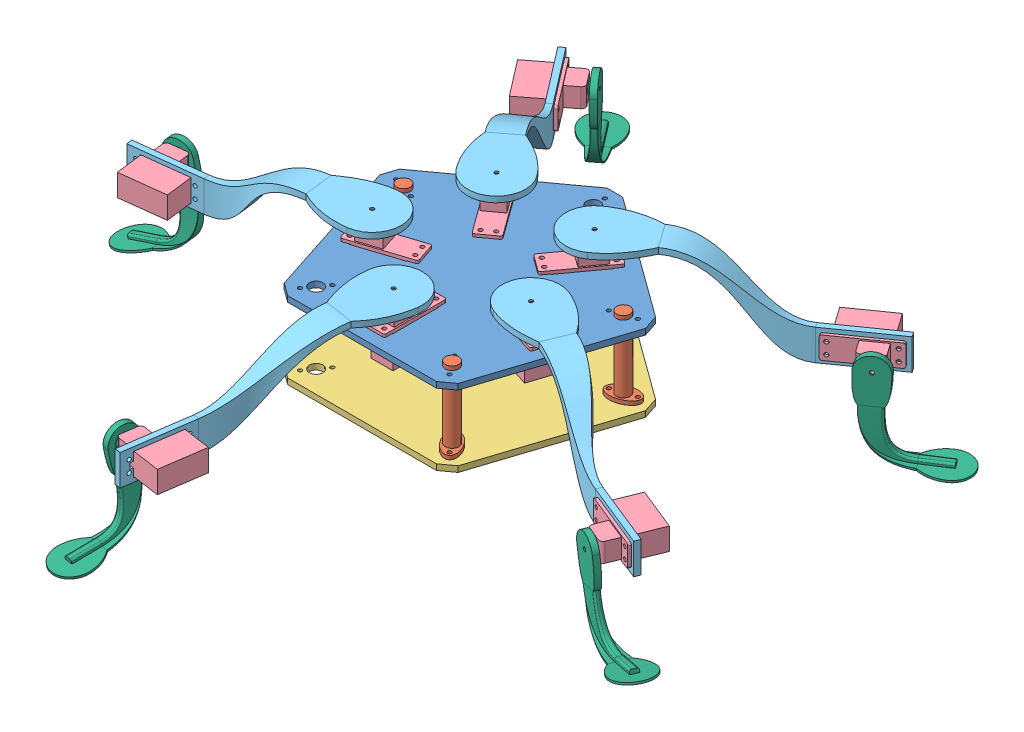
SolidWorks assembly robot1_assemblage, configuration Défaut. Lengths in mm.
Overall size (374.65 85.77 360.41).
25 component instances, 6 part files, 64 mates.
Components (placement in the parent):
- robot1_centre-1: robot1_centre [Défaut] at (-8.837 -2.6667 7.082) size (137.98 3 131.23)
- robot1_pilier-1: robot1_pilier [Défaut] at (48.2264 -19.6667 -11.459) x (0.951057 0 -0.309017) z (0.309017 0 0.951057) size (16 44 9)
- robot1_pilier-2: robot1_pilier [Défaut] at (26.4301 -19.6667 55.6231) x (-0.587785 0 -0.809017) z (0.809017 0 -0.587785) size (16 44 9)
- robot1_pilier-3: robot1_pilier [Défaut] at (-65.9004 -19.6667 -11.459) x (0.951057 0 0.309017) z (-0.309017 0 0.951057) size (16 44 9)
- robot1_fond-1: robot1_fond [Défaut] at (-8.837 -39.6667 7.082) size (137.98 3 131.23)
- servo2-3: servo2 [Défaut] at (17.7099 0.3333 9.8405) x (-0.309017 0 0.951057) z (0 1 0) size (11.43 32.26 30.46)
- servo2-4: servo2 [Défaut] at (-3.257 0.3333 33.182) x (-1 0 0) z (0 1 0) size (11.43 32.26 30.46)
- robot1_bras-1: robot1_bras [Défaut] at (32.4913 11.5713 20.6524) x (0.375024 0 -0.927015) z (0.927015 0 0.375024) size (30 43 135)
- servo2-5: servo2 [Défaut] at (112.2188 -14.5787 63.6934) x (0 -1 0) z (-0.375024 0 0.927015) size (11.43 32.26 30.46)
- robot1_bras-2: robot1_bras [Défaut] at (-8.972 11.5713 50.581) x (0.989601 0 0.143839) z (-0.143839 0 0.989601) size (30 43 135)
- servo2-6: servo2 [Défaut] at (1.7715 0.3333 -17.4718) x (0.809017 0 0.587785) z (0 1 0) size (11.43 32.26 30.46)
- servo2-7: servo2 [Défaut] at (-28.6925 0.3333 -10.7535) x (0.809017 0 -0.587785) z (0 1 0) size (11.43 32.26 30.46)
- servo2-8: servo2 [Défaut] at (-31.9352 0.3333 20.4543) x (-0.309017 0 -0.951057) z (0 1 0) size (11.43 32.26 30.46)
- robot1_bras-3: robot1_bras [Défaut] at (16.6219 11.5713 -28.1887) x (-0.576983 0 -0.816756) z (0.816756 0 -0.576983) size (30 43 135)
- robot1_bras-4: robot1_bras [Défaut] at (-34.2958 11.5713 -28.1887) x (-0.792689 0 0.609626) z (-0.609626 0 -0.792689) size (30 43 135)
- robot1_bras-5: robot1_bras [Défaut] at (-50.2487 11.5713 20.3956) x (0.119564 0 0.992826) z (-0.992826 0 0.119564) size (30 43 135)
- servo2-9: servo2 [Défaut] at (95.9406 -14.5787 -71.9785) x (0 -1 0) z (0.576983 0 0.816756) size (11.43 32.26 30.46)
- servo2-10: servo2 [Défaut] at (-81.2657 -14.8487 -105.6667) x (0 -1 0) z (0.792689 0 -0.609626) size (11.43 32.26 30.46)
- servo2-11: servo2 [Défaut] at (-140.8484 -14.5787 21.2341) x (0 -1 0) z (-0.119564 0 -0.992826) size (11.43 32.26 30.46)
- servo2-12: servo2 [Défaut] at (-31.8207 -14.8487 138.2562) x (0 -1 0) z (-0.989601 0 -0.143839) size (11.43 32.26 30.46)
- robot1_pied-2: robot1_pied [Défaut] at (116.6354 -20.2937 -72.8388) x (0.576983 0 0.816756) z (-0.816415 0.028897 0.576743) size (21.04 49.89 47.7)
- robot1_pied-3: robot1_pied [Défaut] at (-82.9644 -20.5637 -126.3097) x (0.792689 0 -0.609626) z (0.609626 0 0.792689) size (21.04 49.89 47.7)
- robot1_pied-4: robot1_pied [Défaut] at (-159.4662 -20.2937 12.157) x (-0.119564 0 -0.992826) z (0.962903 0.243662 -0.115961) size (21.04 49.89 47.7)
- robot1_pied-5: robot1_pied [Défaut] at (-45.4445 -20.5637 153.8578) x (-0.989601 0 -0.143839) z (0.142047 0.157336 -0.977276) size (21.04 49.89 47.7)
- robot1_pied-6: robot1_pied [Défaut] at (124.1334 -20.2937 80.6362) x (-0.375024 0 0.927015) z (-0.901976 -0.230852 -0.364894) size (21.04 49.89 47.7)
Mates (geometry in assembly coordinates):
- Coaxiale4: concentric aligned: circle of robot1_centre-1; circle of robot1_pilier-1
- Coaxiale5: concentric aligned: circle of robot1_centre-1; circle of robot1_pilier-2
- Coaxiale6: concentric aligned: circle of robot1_centre-1; circle of robot1_pilier-3
- Coaxiale7: concentric aligned: circle of robot1_centre-1; circle of robot1_pilier-1
- Coaxiale8: concentric aligned: circle of robot1_centre-1; circle of robot1_pilier-2
- Coaxiale9: concentric aligned: circle of robot1_centre-1; circle of robot1_pilier-3
- Coïncidente15: coincident anti-aligned: plane of robot1_centre-1 through (-8.837 -2.6667 7.082) normal (0 -1 0); plane of robot1_pilier-3 through (-65.9004 -2.6667 -11.459) normal (0 1 0)
- Coïncidente16: coincident anti-aligned: plane of robot1_centre-1 through (-8.837 -2.6667 7.082) normal (0 -1 0); plane of robot1_pilier-1 through (48.2264 -2.6667 -11.459) normal (0 1 0)
- Coïncidente17: coincident anti-aligned: plane of robot1_centre-1 through (-8.837 -2.6667 7.082) normal (0 -1 0); plane of robot1_pilier-2 through (26.4301 -2.6667 55.6231) normal (0 1 0)
- Coaxiale10: concentric aligned: circle of robot1_pilier-3; circle of robot1_fond-1
- Coaxiale11: concentric aligned: circle of robot1_pilier-1; circle of robot1_fond-1
- Coaxiale12: concentric aligned: circle of robot1_pilier-2; circle of robot1_fond-1
- Coaxiale13: concentric aligned: circle of robot1_pilier-1; circle of robot1_fond-1
- Coïncidente22: coincident anti-aligned: plane of robot1_pilier-1 through (48.2264 -36.6667 -11.459) normal (0 -1 0); plane of robot1_fond-1 through (-8.837 -36.6667 7.082) normal (0 1 0)
- Coïncidente25: coincident anti-aligned: plane of robot1_centre-1 through (14.1779 0.3333 20.7111) normal (0.309017 0 -0.951057); plane of servo2-3 through (14.1779 0.3333 20.7111) normal (-0.309017 0 0.951057)
- Coïncidente26: coincident anti-aligned: plane of robot1_centre-1 through (14.1779 0.3333 20.7111) normal (0.951057 0 0.309017); plane of servo2-3 through (14.1779 0.3333 20.7111) normal (-0.951057 0 -0.309017)
- Coïncidente27: coincident anti-aligned: plane of robot1_centre-1 through (-8.837 0.3333 7.082) normal (0 1 0); plane of servo2-3 through (36.4021 0.3333 27.9322) normal (0 -1 0)
- Coïncidente32: coincident anti-aligned: plane of robot1_centre-1 through (-14.687 0.3333 33.182) normal (0 0 1); plane of servo2-4 through (-14.687 0.3333 33.182) normal (0 0 -1)
- Coïncidente33: coincident anti-aligned: plane of robot1_centre-1 through (-14.687 0.3333 33.182) normal (1 0 0); plane of servo2-4 through (-14.687 0.3333 33.182) normal (-1 0 0)
- Coïncidente34: coincident anti-aligned: plane of robot1_centre-1 through (-8.837 0.3333 7.082) normal (0 1 0); plane of servo2-4 through (-14.687 0.3333 56.55) normal (0 -1 0)
- Coaxiale14: concentric aligned: circle of servo2-3; circle of robot1_bras-1
- Coïncidente35: coincident anti-aligned: plane of servo2-3 through (31.7188 13.7713 23.03) normal (0 1 0); plane of robot1_bras-1 through (32.4913 13.7713 20.6524) normal (0 -1 0)
- Coïncidente36: coincident anti-aligned: plane of robot1_bras-1 through (112.2188 -14.5787 63.6934) normal (0 -1 0); plane of servo2-5 through (112.2188 -14.5787 63.6934) normal (0 1 0)
- Coïncidente37: coincident anti-aligned: plane of robot1_bras-1 through (112.2188 -14.5787 63.6934) normal (0.927015 0 0.375024); plane of servo2-5 through (112.2188 -26.0087 63.6934) normal (-0.927015 0 -0.375024)
- Coïncidente39: coincident anti-aligned: plane of robot1_bras-1 through (28.7411 11.5713 29.9225) normal (-0.375024 0 0.927015); plane of servo2-5 through (133.8813 -26.0087 72.457) normal (0.375024 0 -0.927015)
- Coaxiale15: concentric aligned: circle of servo2-4; circle of robot1_bras-2
- Coïncidente40: coincident anti-aligned: plane of servo2-4 through (-11.472 13.7713 50.581) normal (0 1 0); plane of robot1_bras-2 through (-8.972 13.7713 50.581) normal (0 -1 0)
- Coïncidente41: coincident anti-aligned: plane of robot1_centre-1 through (1.7715 0.3333 -17.4718) normal (0.809017 0 0.587785); plane of servo2-6 through (1.7715 0.3333 -17.4718) normal (-0.809017 0 -0.587785)
- Coïncidente42: coincident anti-aligned: plane of robot1_centre-1 through (11.237 0.3333 -10.5948) normal (0.587785 0 -0.809017); plane of servo2-6 through (11.0185 0.3333 -10.7535) normal (-0.587785 0 0.809017)
- Coïncidente43: coincident anti-aligned: plane of robot1_centre-1 through (-8.837 0.3333 7.082) normal (0 1 0); plane of servo2-6 through (24.7539 0.3333 -29.6586) normal (0 -1 0)
- Coïncidente44: coincident anti-aligned: plane of robot1_centre-1 through (-19.4454 0.3333 -17.4718) normal (-0.809017 0 0.587785); plane of servo2-7 through (-19.4454 0.3333 -17.4718) normal (0.809017 0 -0.587785)
- Coïncidente45: coincident anti-aligned: plane of robot1_centre-1 through (-19.4454 0.3333 -17.4718) normal (-0.587785 0 -0.809017); plane of servo2-7 through (-19.4454 0.3333 -17.4718) normal (0.587785 0 0.809017)
- Coïncidente46: coincident anti-aligned: plane of robot1_centre-1 through (-8.837 0.3333 7.082) normal (0 1 0); plane of servo2-7 through (-33.1808 0.3333 -36.377) normal (0 -1 0)
- Coïncidente47: coincident anti-aligned: plane of robot1_centre-1 through (-35.4673 0.3333 9.5837) normal (0.309017 0 0.951057); plane of servo2-8 through (-35.4673 0.3333 9.5837) normal (-0.309017 0 -0.951057)
- Coïncidente48: coincident anti-aligned: plane of robot1_centre-1 through (-35.4673 0.3333 9.5837) normal (-0.951057 0 0.309017); plane of servo2-8 through (-35.4673 0.3333 9.5837) normal (0.951057 0 -0.309017)
- Coïncidente49: coincident anti-aligned: plane of robot1_centre-1 through (-8.837 0.3333 7.082) normal (0 1 0); plane of servo2-8 through (-57.6916 0.3333 16.8048) normal (0 -1 0)
- Coaxiale16: concentric aligned: circle of servo2-6; circle of robot1_bras-3
- Coïncidente50: coincident anti-aligned: plane of servo2-6 through (18.6444 13.7713 -26.7193) normal (0 1 0); plane of robot1_bras-3 through (16.6219 13.7713 -28.1887) normal (0 -1 0)
- Coaxiale17: concentric aligned: circle of servo2-7; circle of robot1_bras-4
- Coïncidente51: coincident anti-aligned: plane of servo2-7 through (-32.2733 13.7713 -29.6582) normal (0 1 0); plane of robot1_bras-4 through (-34.2958 13.7713 -28.1887) normal (0 -1 0)
- Coaxiale18: concentric aligned: circle of servo2-8; circle of robot1_bras-5
- Coïncidente52: coincident anti-aligned: plane of servo2-8 through (-51.0212 13.7713 18.0179) normal (0 1 0); plane of robot1_bras-5 through (-50.2487 13.7713 20.3956) normal (0 -1 0)
- Coïncidente53: coincident anti-aligned: plane of robot1_bras-3 through (95.9406 -14.5787 -71.9785) normal (0 -1 0); plane of servo2-9 through (95.9406 -14.5787 -71.9785) normal (0 1 0)
- Coïncidente54: coincident anti-aligned: plane of robot1_bras-3 through (95.9406 -14.5787 -71.9785) normal (0.816756 0 -0.576983); plane of servo2-9 through (95.9406 -26.0087 -71.9785) normal (-0.816756 0 0.576983)
- Coïncidente55: coincident anti-aligned: plane of robot1_bras-3 through (22.3917 11.5713 -20.0212) normal (0.576983 0 0.816756); plane of servo2-9 through (115.0265 -26.0087 -85.4615) normal (-0.576983 0 -0.816756)
- Coïncidente56: coincident anti-aligned: plane of robot1_bras-4 through (-81.2657 -14.5787 -105.6667) normal (-0.609626 0 -0.792689); plane of servo2-10 through (-81.2657 -26.2787 -105.6667) normal (0.609626 0 0.792689)
- Coïncidente57: coincident anti-aligned: plane of robot1_bras-4 through (-81.2657 -26.2787 -105.6667) normal (0 1 0); plane of servo2-10 through (-81.2657 -26.2787 -105.6667) normal (0 -1 0)
- Coïncidente58: coincident anti-aligned: plane of robot1_bras-4 through (-26.3689 11.5713 -34.285) normal (0.792689 0 -0.609626); plane of servo2-10 through (-95.5114 -26.2787 -124.1903) normal (-0.792689 0 0.609626)
- Coïncidente59: coincident anti-aligned: plane of robot1_bras-5 through (-140.8484 -14.5787 21.2341) normal (0 -1 0); plane of servo2-11 through (-140.8484 -14.5787 21.2341) normal (0 1 0)
- Coïncidente60: coincident anti-aligned: plane of robot1_bras-5 through (-140.8484 -14.5787 21.2341) normal (-0.992826 0 0.119564); plane of servo2-11 through (-140.8484 -26.0087 21.2341) normal (0.992826 0 -0.119564)
- Coïncidente61: coincident anti-aligned: plane of robot1_bras-5 through (-51.4443 11.5713 10.4673) normal (-0.119564 0 -0.992826); plane of servo2-11 through (-164.0487 -26.0087 24.028) normal (0.119564 0 0.992826)
- Coïncidente62: coincident anti-aligned: plane of robot1_bras-2 through (-31.8207 -14.5787 138.2562) normal (-0.143839 0 0.989601); plane of servo2-12 through (-31.8207 -26.2787 138.2562) normal (0.143839 0 -0.989601)
- Coïncidente63: coincident anti-aligned: plane of robot1_bras-2 through (-31.8207 -26.2787 138.2562) normal (0 1 0); plane of servo2-12 through (-31.8207 -26.2787 138.2562) normal (0 -1 0)
- Coïncidente64: coincident anti-aligned: plane of robot1_bras-2 through (-18.868 11.5713 49.1427) normal (-0.989601 0 -0.143839); plane of servo2-12 through (-35.1819 -26.2787 161.3812) normal (0.989601 0 0.143839)
- Coaxiale19: concentric aligned: circle of servo2-9; circle of robot1_pied-2
- Coïncidente65: coincident anti-aligned: plane of servo2-9 through (117.9048 -22.7937 -71.0419) normal (0.576983 0 0.816756); plane of robot1_pied-2 through (117.9048 -20.2937 -71.0419) normal (-0.576983 0 -0.816756)
- Coaxiale20: concentric aligned: circle of servo2-10; circle of robot1_pied-3
- Coïncidente66: coincident anti-aligned: plane of servo2-10 through (-81.2204 -23.0637 -127.6508) normal (0.792689 0 -0.609626); plane of robot1_pied-3 through (-81.2204 -20.5637 -127.6508) normal (-0.792689 0 0.609626)
- Coaxiale22: concentric: circle of servo2-11; circle of robot1_pied-4
- Coïncidente67: coincident anti-aligned: plane of servo2-11 through (-159.7293 -22.7937 9.9728) normal (-0.119564 0 -0.992826); plane of robot1_pied-4 through (-159.7293 -20.2937 9.9728) normal (0.119564 0 0.992826)
- Coaxiale23: concentric: circle of servo2-12; circle of robot1_pied-5
- Coïncidente68: coincident anti-aligned: plane of servo2-12 through (-47.6216 -23.0637 153.5414) normal (-0.989601 0 -0.143839); plane of robot1_pied-5 through (-47.6216 -20.5637 153.5414) normal (0.989601 0 0.143839)
- Coaxiale24: concentric: circle of servo2-5; circle of robot1_pied-6
- Coïncidente69: coincident anti-aligned: plane of servo2-5 through (123.3084 -22.7937 82.6757) normal (-0.375024 0 0.927015); plane of robot1_pied-6 through (123.3084 -20.2937 82.6757) normal (0.375024 0 -0.927015)
